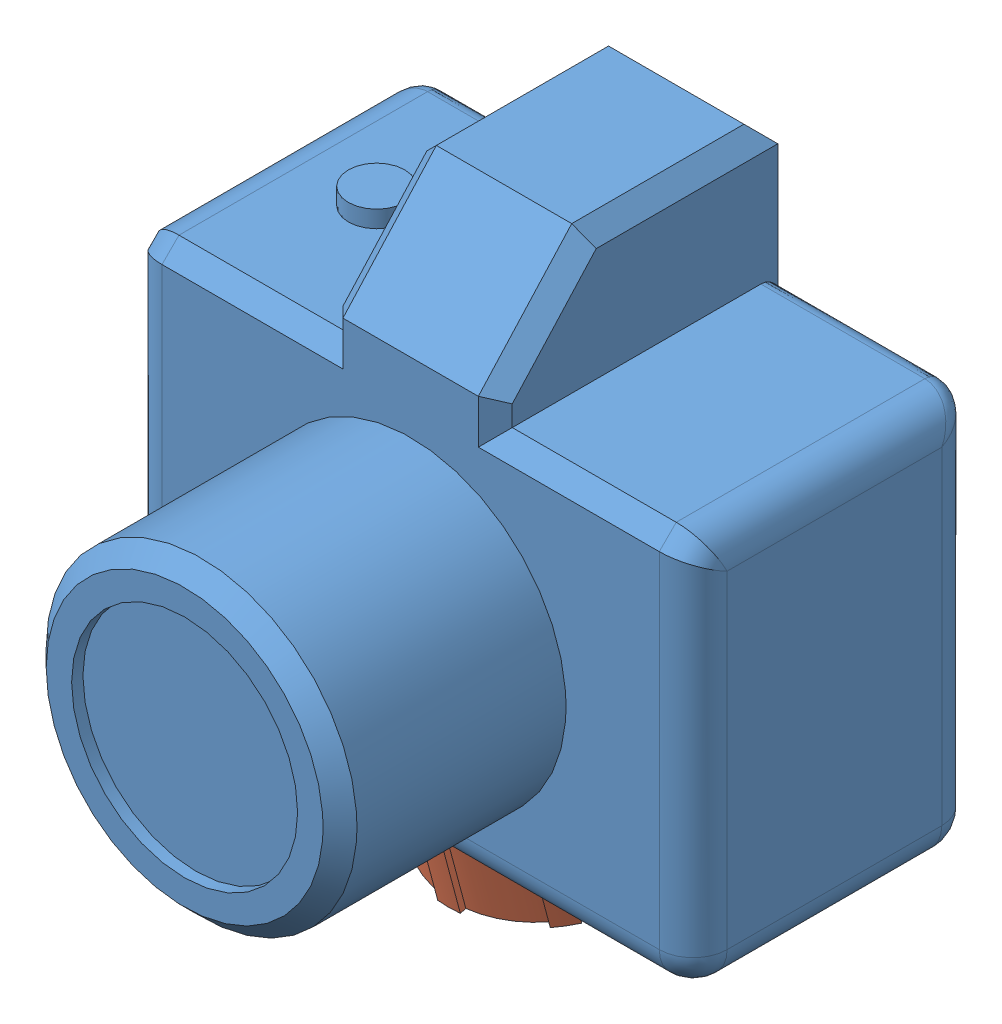
SolidWorks assembly camera_bar, configuration 默认. Lengths in mm.
Overall size (100 105.86 90).
2 component instances, 2 part files, 5 mates.
Components (placement in the parent):
- camera-1: camera [默认] at origin size (100 93 90)
- bar-2: bar [默认] at (0 -7.4237 -1.9892) x (0 -0.258819 0.965926) z (-1 0 0) size (42 13.31 42)
Mates (geometry in assembly coordinates):
- 同心1: concentric: cylinder of camera-1 through (0 5 0) axis (0 -1 0) radius 10
- 重合2: coincident: plane of camera-1 through (0 0 0) normal (0 -1 0)
- 重合3: coincident: plane of camera-1 through (0 0 0) normal (0 -1 0); plane of bar-2 through (34 0 -21.9674) normal (0 1 0)
- 同心2: concentric: cylinder of camera-1 through (0 5 0) axis (0 -1 0) radius 10; cylinder of bar-2 through (0 -4 0) axis (0 1 0) radius 12.5
- 平行3: parallel: line of camera-1 through (44 0 19) axis (-1 0 0); plane of bar-2 through (0 -7.4237 -1.9892) normal (0 -0.258819 0.965926)
